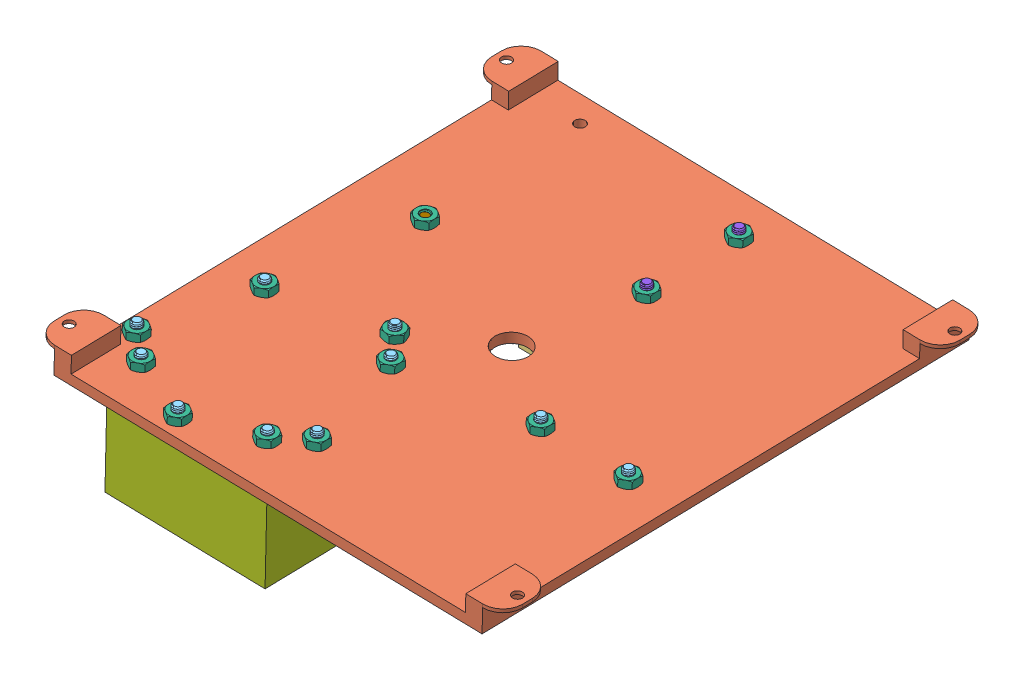
SolidWorks assembly Platform and Parts Assembly, configuration Default. Lengths in mm.
Overall size (140.75 43.07 149.11).
121 component instances, 45 part files, 55 mates.
Components (placement in the parent):
- L298N Motor Driver-1: L298N Motor Driver [Default] at (2.2054 13.8777 390.8162) x (-0.999336 0.034718 0.011037) z (0.010625 -0.012048 0.999871) size (43.5 26 43.5)
- base platform-2: base platform [Default] at (33.5926 16.2793 348.5062) x (-0.999336 0.034718 0.011037) z (0.010625 -0.012048 0.999871) size (139 8 147.5)
- battery holder-1: battery holder [Default] at (70.7076 1.8808 356.6895) x (-0.999336 0.034718 0.011037) z (0.010625 -0.012048 0.999871) size (32 20 15)
- Arduino holder-2: Arduino holder [Default] at (7.3967 9.4765 306.6172) x (0.999336 -0.034718 -0.011037) z (-0.010625 0.012048 -0.999871) size (70.58 5.2 55.34)
- arduino uno-3: arduino uno [Default] at (-25.8848 10.9442 280.3151) x (-0.010625 0.012048 -0.999871) z (-0.999336 0.034718 0.011037) size (53.34 15.26 74.94)
  - arduino uno.STEP-1: arduino uno.STEP [Default] at origin size (53.34 15.26 74.94)
    - USB type b.STEP-1: USB type b.STEP [Default] at (-38.02 0.43 6.35) size (13.91 15.21 16.51)
      - USB SHELL.STEP-1: USB SHELL.STEP [Default] at origin size (13.91 15.21 16.51)
      - USB core.STEP-1: USB core.STEP [Default] at origin size (11.3 10.68 15.75)
      - usb top contact.STEP-1: usb top contact.STEP [Default] at (1.25 6.09 -0.38) size (1 9.67 13.76)
      - usb btm contact.STEP-1: usb btm contact.STEP [Default] at (1.25 4.41 -0.38) size (1 6.84 11.76)
      - usb btm contact.STEP-2: usb btm contact.STEP [Default] at (-1.25 4.41 -0.38) size (1 6.84 11.76)
      - usb top contact.STEP-2: usb top contact.STEP [Default] at (-1.25 6.09 -0.38) size (1 9.67 13.76)
    - dip28.STEP-1: dip28.STEP [Default] at (-16.383 1.5 -46.355) x (0 0 -1) z (1 0 0) size (35.48 7.37 10.1)
      - dip28-0.STEP-1: dip28-0.STEP [Default] at origin size (35.48 2.8 10.1)
      - dip socket pin.STEP-1: dip socket pin.STEP [Default] at (16.51 2.8 -3.81) size (1.7 7.37 1.7)
      - dip socket pin.STEP-2: dip socket pin.STEP [Default] at (16.51 2.8 3.81) size (1.7 7.37 1.7)
      - dip socket pin.STEP-3: dip socket pin.STEP [Default] at (13.97 2.8 -3.81) size (1.7 7.37 1.7)
      - dip socket pin.STEP-4: dip socket pin.STEP [Default] at (13.97 2.8 3.81) size (1.7 7.37 1.7)
      - dip socket pin.STEP-5: dip socket pin.STEP [Default] at (11.43 2.8 -3.81) size (1.7 7.37 1.7)
      - dip socket pin.STEP-6: dip socket pin.STEP [Default] at (11.43 2.8 3.81) size (1.7 7.37 1.7)
      - dip socket pin.STEP-7: dip socket pin.STEP [Default] at (8.89 2.8 -3.81) size (1.7 7.37 1.7)
      - dip socket pin.STEP-8: dip socket pin.STEP [Default] at (8.89 2.8 3.81) size (1.7 7.37 1.7)
      - dip socket pin.STEP-9: dip socket pin.STEP [Default] at (6.35 2.8 -3.81) size (1.7 7.37 1.7)
      - dip socket pin.STEP-10: dip socket pin.STEP [Default] at (6.35 2.8 3.81) size (1.7 7.37 1.7)
      - dip socket pin.STEP-11: dip socket pin.STEP [Default] at (3.81 2.8 -3.81) size (1.7 7.37 1.7)
      - dip socket pin.STEP-12: dip socket pin.STEP [Default] at (3.81 2.8 3.81) size (1.7 7.37 1.7)
      - dip socket pin.STEP-13: dip socket pin.STEP [Default] at (1.27 2.8 -3.81) size (1.7 7.37 1.7)
      - dip socket pin.STEP-14: dip socket pin.STEP [Default] at (1.27 2.8 3.81) size (1.7 7.37 1.7)
      - dip socket pin.STEP-15: dip socket pin.STEP [Default] at (-1.27 2.8 -3.81) size (1.7 7.37 1.7)
      - dip socket pin.STEP-16: dip socket pin.STEP [Default] at (-1.27 2.8 3.81) size (1.7 7.37 1.7)
      - dip socket pin.STEP-17: dip socket pin.STEP [Default] at (-3.81 2.8 -3.81) size (1.7 7.37 1.7)
      - dip socket pin.STEP-18: dip socket pin.STEP [Default] at (-3.81 2.8 3.81) size (1.7 7.37 1.7)
      - dip socket pin.STEP-19: dip socket pin.STEP [Default] at (-6.35 2.8 -3.81) size (1.7 7.37 1.7)
      - dip socket pin.STEP-20: dip socket pin.STEP [Default] at (-6.35 2.8 3.81) size (1.7 7.37 1.7)
      - dip socket pin.STEP-21: dip socket pin.STEP [Default] at (-8.89 2.8 -3.81) size (1.7 7.37 1.7)
      - dip socket pin.STEP-22: dip socket pin.STEP [Default] at (-8.89 2.8 3.81) size (1.7 7.37 1.7)
      - dip socket pin.STEP-23: dip socket pin.STEP [Default] at (-11.43 2.8 -3.81) size (1.7 7.37 1.7)
      - dip socket pin.STEP-24: dip socket pin.STEP [Default] at (-11.43 2.8 3.81) size (1.7 7.37 1.7)
      - dip socket pin.STEP-25: dip socket pin.STEP [Default] at (-13.97 2.8 -3.81) size (1.7 7.37 1.7)
      - dip socket pin.STEP-26: dip socket pin.STEP [Default] at (-13.97 2.8 3.81) size (1.7 7.37 1.7)
      - dip socket pin.STEP-27: dip socket pin.STEP [Default] at (-16.51 2.8 -3.81) size (1.7 7.37 1.7)
      - dip socket pin.STEP-28: dip socket pin.STEP [Default] at (-16.51 2.8 3.81) size (1.7 7.37 1.7)
    - RESET BUTTON.STEP-1: RESET BUTTON.STEP [Default] at (-49.403 0 -6.35) size (6.2 3.1 9.6)
      - RESET CORE.STEP-1: RESET CORE.STEP [Default] at (0 0.1 0) x (-1 0 0) z (0 0 -1) size (6.2 3.1 9.6)
      - RESET.STEP-1: RESET.STEP [Default] at (0 0.1 0) x (0 0 1) z (-1 0 0) size (7.3 2 6.2)
    - unoboard blue.STEP-1: unoboard blue.STEP [Default] at origin size (53.34 1.65 68.58)
    - 47uf CAP Dcase.STEP-1: 47uf CAP Dcase.STEP [Default] at (-9.4141 0 -18.4991) x (0 0 -1) z (1 0 0) size (6.6 5.81 8)
    - power jack.STEP-1: power jack.STEP [Default] at (-7.675 0 1.905) size (11.2 15.2 15.9)
    - 47uf CAP Dcase.STEP-2: 47uf CAP Dcase.STEP [Default] at (-9.4141 0 -25.7132) x (0 0 -1) z (1 0 0) size (6.6 5.81 8)
    - crystal.STEP-1: crystal.STEP [Default] at (-26.162 0 -18.923) x (1 0 0) z (0 0 -1) size (4 5 11)
    - 2pin_header__02.STEP-1: 2pin_header__02.STEP [Default] at (-46.23 0 -15.75) size (5 11.75 2.54)
    - nano - reg.STEP-1: nano - reg.STEP [Default] at (-17.399 0 -7.747) size (6.5 1.69 8.3)
    - led.STEP-1: led.STEP [Default] at (-34.29 0 -27.94) x (0 0 1) z (-1 0 0) size (4 0.85 1.47)
    - 2pin_header__02.STEP-2: 2pin_header__02.STEP [Default] at (-30.43 0 -64.91) x (0 0 1) z (-1 0 0) size (5 11.75 2.54)
    - 2pin_header__02.STEP-3: 2pin_header__02.STEP [Default] at (-27.89 0 -64.91) x (0 0 1) z (-1 0 0) size (5 11.75 2.54)
    - 2pin_header__02.STEP-4: 2pin_header__02.STEP [Default] at (-25.35 0 -64.91) x (0 0 1) z (-1 0 0) size (5 11.75 2.54)
    - 2pin_header__02.STEP-5: 2pin_header__02.STEP [Default] at (-46.23 0 -18.29) size (5 11.75 2.54)
    - 2pin_header__02.STEP-6: 2pin_header__02.STEP [Default] at (-46.23 0 -20.83) size (5 11.75 2.54)
    - atmega16u2.STEP-1: atmega16u2.STEP [Default] at (-34.671 0.06 -20) x (1 0 0) z (0 0 -1) size (5.5 1.01 5.5)
    - led.STEP-2: led.STEP [Default] at (-36.83 0 -27.94) x (0 0 1) z (-1 0 0) size (4 0.85 1.47)
    - led.STEP-3: led.STEP [Default] at (-42.037 0 -27.94) x (0 0 1) z (-1 0 0) size (4 0.85 1.47)
    - led.STEP-4: led.STEP [Default] at (-36.576 0 -58.42) x (0 0 1) z (-1 0 0) size (4 0.85 1.47)
    - 8 PORT HEADER.STEP-1: 8 PORT HEADER.STEP [Default] at (-50.8 0 -45.72) x (0 0 -1) z (1 0 0) size (20.32 10.51 2.41)
    - 8 PORT HEADER.STEP-2: 8 PORT HEADER.STEP [Default] at (-2.54 0 -27.94) x (0 0 -1) z (1 0 0) size (20.32 10.51 2.41)
    - 6 PORT HEADER.STEP-1: 6 PORT HEADER.STEP [Default] at (-2.54 0 -50.8) x (0 0 -1) z (1 0 0) size (15.24 10.51 2.41)
    - 10 PORT HEADER.STEP-1: 10 PORT HEADER.STEP [Default] at (-50.8 0 -18.796) x (0 0 -1) z (1 0 0) size (25.4 10.51 2.41)
    - ATMEL328P.STEP-1: ATMEL328P.STEP [Default] at (-16.383 4.3 -46.355) x (0 0 -1) z (1 0 0) size (35 7.27 7.87)
    - 102 RESISTOR PACK.STEP-1: 102 RESISTOR PACK.STEP [Default] at (-33.782 0 -58.42) size (3.2 0.46 3)
    - 102 RESISTOR PACK.STEP-2: 102 RESISTOR PACK.STEP [Default] at (-39.37 0 -27.94) size (3.2 0.46 3)
    - 103 RESISTOR PACK.STEP-1: 103 RESISTOR PACK.STEP [Default] at (-23.876 0 -27.94) size (3.2 0.46 3)
    - 220 RESISTOR PACK.STEP-1: 220 RESISTOR PACK.STEP [Default] at (-36.83 0 -12.827) size (3.2 0.46 3)
    - 16mhz crystal - measured.STEP-1: 16mhz crystal - measured.STEP [Default] at (-24.892 0 -41.275) x (0 0 -1) z (1 0 0) size (3.4 0.8 2)
    - PADS001.STEP-1: PADS001.STEP [Default] at (-39.878 0.1 -18.288) x (-1 0 0) z (0 0 1) size (4.54 0.1 4.54)
    - 603 cap on pad.STEP-1: 603 cap on pad.STEP [Default] at (-44.45 0 -27.94) x (0 0 -1) z (1 0 0) size (2.76 0.9 1.03)
    - ssot3.STEP-1: ssot3.STEP [Default] at (-26.5 0 -8.128) x (-1 0 0) z (0 0 -1) size (3 1.13 3.09)
    - mf-msmf050-2.STEP-1: mf-msmf050-2.STEP [Default] at (-26.5 0 -4.064) size (5.86 1.02 3.72)
    - 603 cap on pad.STEP-2: 603 cap on pad.STEP [Default] at (-29.845 0 -27.94) x (0 0 -1) z (1 0 0) size (2.76 0.9 1.03)
    - 603 cap on pad.STEP-3: 603 cap on pad.STEP [Default] at (-31.496 0 -27.94) x (0 0 -1) z (1 0 0) size (2.76 0.9 1.03)
    - lmv358.STEP-1: lmv358.STEP [Default] at (-15.24 0 -21.971) x (0 0 -1) z (1 0 0) size (3.7 1.4 2.9)
    - 603 cap on pad.STEP-4: 603 cap on pad.STEP [Default] at (-15.24 0 -18.415) size (2.76 0.9 1.03)
    - 603 cap on pad.STEP-5: 603 cap on pad.STEP [Default] at (-29.845 0 -12.065) x (0 0 1) z (-1 0 0) size (2.76 0.9 1.03)
    - 603 cap on pad.STEP-6: 603 cap on pad.STEP [Default] at (-29.591 0 -22.352) x (0 0 1) z (-1 0 0) size (2.76 0.9 1.03)
    - 603 cap on pad.STEP-7: 603 cap on pad.STEP [Default] at (-29.591 0 -16.002) x (0 0 1) z (-1 0 0) size (2.76 0.9 1.03)
    - 603 cap on pad.STEP-8: 603 cap on pad.STEP [Default] at (-41.91 0 -12.7) x (0 0 1) z (-1 0 0) size (2.76 0.9 1.03)
    - lp2985dgkr.STEP-1: lp2985dgkr.STEP [Default] at (-20.32 0 -19.05) x (0 0 -1) z (1 0 0) size (5.85 1.1 3)
    - cd1206 diode.STEP-1: cd1206 diode.STEP [Default] at (-27.94 0 -59.436) x (0 0 -1) z (1 0 0) size (2.01 0.96 5)
    - cd1206 diode.STEP-2: cd1206 diode.STEP [Default] at (-46.228 0 -13.081) x (0 0 1) z (-1 0 0) size (2.01 0.96 5)
    - 603 resistor.STEP-1: 603 resistor.STEP [Default] at (-29.591 0 -19.05) x (0 0 1) z (-1 0 0) size (2.36 0.61 1.02)
    - blm21.STEP-1: blm21.STEP [Default] at (-45.085 0 -7.62) x (0 0 -1) z (1 0 0) size (2.78 0.95 1.32)
    - m7 diode.STEP-1: m7 diode.STEP [Default] at (-2.794 0 -21.59) x (0 0 -1) z (1 0 0) size (6.66 2.35 2.5)
    - MLC0603.STEP-1: MLC0603.STEP [Default] at (-33.655 0 -12.827) x (0 0 -1) z (1 0 0) size (2.36 0.6 1.02)
    - MLC0603.STEP-2: MLC0603.STEP [Default] at (-39.37 0 -12.827) x (0 0 -1) z (1 0 0) size (2.36 0.6 1.02)
- 18650 Li Ion Battery-2: 18650 Li Ion Battery [Default] at (70.4769 3.1813 331.7044) x (0.999944 0.000054 -0.010625) z (0.010625 -0.012048 0.999871) size (18 18 65.81)
- 3M 8mm 0.5t bolt-2: 3M 8mm 0.5t bolt [92095A181] at (-16.4428 11.1549 409.734) x (0.999393 -0.034851 0.000173) z (-0.034846 -0.999325 -0.011671) size (5.7 5.7 9.83)
- 3M 8mm 0.5t bolt-3: 3M 8mm 0.5t bolt [92095A181] at (-16.8406 11.606 372.2888) x (0.999393 -0.034851 0.000173) z (-0.034846 -0.999325 -0.011671) size (5.7 5.7 9.83)
- 3M 8mm 0.5t bolt-4: 3M 8mm 0.5t bolt [92095A181] at (20.9824 9.8547 409.3206) x (0.999393 -0.034851 0.000173) z (-0.034846 -0.999325 -0.011671) size (5.7 5.7 9.83)
- 3M 8mm 0.5t bolt-5: 3M 8mm 0.5t bolt [92095A181] at (20.5845 10.3059 371.8755) x (0.999393 -0.034851 0.000173) z (-0.034846 -0.999325 -0.011671) size (5.7 5.7 9.83)
- 3M 0.5t nut-1: 3M 0.5t nut [91828A211] at (-16.1866 18.4999 409.8198) x (0.999393 -0.034851 0.000173) z (-0.034846 -0.999325 -0.011671) size (5.5 6.35 2.78)
- 3M 0.5t nut-5: 3M 0.5t nut [91828A211] at (21.2385 17.1997 409.4064) x (0.999393 -0.034851 0.000173) z (-0.034846 -0.999325 -0.011671) size (5.5 6.35 2.78)
- 3M 0.5t nut-6: 3M 0.5t nut [91828A211] at (-16.5845 18.9511 372.3746) x (0.999393 -0.034851 0.000173) z (-0.034846 -0.999325 -0.011671) size (5.5 6.35 2.78)
- 3M 0.5t nut-7: 3M 0.5t nut [91828A211] at (20.8406 17.6509 371.9613) x (0.999393 -0.034851 0.000173) z (-0.034846 -0.999325 -0.011671) size (5.5 6.35 2.78)
- 3M 8mm 0.5t bolt-6: 3M 8mm 0.5t bolt [92095A181] at (84.0348 8.6841 364.1308) x (0.999393 -0.034851 0.000173) z (-0.034846 -0.999325 -0.011671) size (5.7 5.7 9.83)
- 3M 8mm 0.5t bolt-7: 3M 8mm 0.5t bolt [92095A181] at (58.0521 9.5868 364.4178) x (0.999393 -0.034851 0.000173) z (-0.034846 -0.999325 -0.011671) size (5.7 5.7 9.83)
- 3M 0.5t nut-8: 3M 0.5t nut [91828A211] at (84.2735 15.5295 364.2107) x (0.999393 -0.034851 0.000173) z (-0.034846 -0.999325 -0.011671) size (5.5 6.35 2.78)
- 3M 0.5t nut-9: 3M 0.5t nut [91828A211] at (58.2908 16.4322 364.4977) x (0.999393 -0.034851 0.000173) z (-0.034846 -0.999325 -0.011671) size (5.5 6.35 2.78)
- Motor Enclosure-2: Motor Enclosure [Default] at (-21.7812 14.9883 367.3314) x (0.999336 -0.034718 -0.011037) z (-0.034846 -0.999325 -0.011671) size (59.5 59.5 31)
- 3M 8mm 0.5t bolt-8: 3M 8mm 0.5t bolt [92095A181] at (-24.4931 12.0151 402.954) x (0.999393 -0.034851 0.000173) z (-0.034846 -0.999325 -0.011671) size (5.7 5.7 9.83)
- 3M 8mm 0.5t bolt-9: 3M 8mm 0.5t bolt [92095A181] at (2.3972 10.9072 417.5318) x (0.999393 -0.034851 0.000173) z (-0.034846 -0.999325 -0.011671) size (5.7 5.7 9.83)
- 3M 8mm 0.5t bolt-10: 3M 8mm 0.5t bolt [92095A181] at (28.9714 10.1577 402.3635) x (0.999393 -0.034851 0.000173) z (-0.034846 -0.999325 -0.011671) size (5.7 5.7 9.83)
- 3M 8mm 0.5t bolt-11: 3M 8mm 0.5t bolt [92095A181] at (13.8208 11.1351 363.9063) x (0.472551 -0.006186 -0.881282) z (-0.034846 -0.999325 -0.011671) size (5.7 5.7 9.83)
- 3M 0.5t nut-10: 3M 0.5t nut [91828A211] at (-24.2544 18.8605 403.034) x (0.999393 -0.034851 0.000173) z (-0.034846 -0.999325 -0.011671) size (5.5 6.35 2.78)
- 3M 0.5t nut-11: 3M 0.5t nut [91828A211] at (14.0595 17.9805 363.9862) x (-0.783157 0.034559 -0.620863) z (-0.034846 -0.999325 -0.011671) size (5.5 6.35 2.78)
- 3M 0.5t nut-14: 3M 0.5t nut [91828A211] at (29.2101 17.0031 402.4435) x (0.999393 -0.034851 0.000173) z (-0.034846 -0.999325 -0.011671) size (5.5 6.35 2.78)
- 3M 0.5t nut-15: 3M 0.5t nut [91828A211] at (2.6359 17.7526 417.6118) x (0.999393 -0.034851 0.000173) z (-0.034846 -0.999325 -0.011671) size (5.5 6.35 2.78)
- 3M 12mm 0.5t bolt-5: 3M 12mm 0.5t bolt [92095A183] at (40.4317 6.5741 315.1223) x (0.899466 -0.02627 -0.4362) z (-0.034846 -0.999325 -0.011671) size (5.7 5.7 13.83)
- 3M 12mm 0.5t bolt-6: 3M 12mm 0.5t bolt [92095A183] at (40.1348 6.9107 287.1859) x (0.999393 -0.034846 -0.000203) z (-0.034846 -0.999325 -0.011671) size (5.7 5.7 13.83)
- 3M 0.5t nut-16: 3M 0.5t nut [91828A211] at (40.5199 17.9532 287.3149) x (0.999393 -0.034846 -0.000203) z (-0.034846 -0.999325 -0.011671) size (5.5 6.35 2.78)
- 3M 0.5t nut-17: 3M 0.5t nut [91828A211] at (40.8168 17.6166 315.2513) x (0.999393 -0.034846 -0.000203) z (-0.034846 -0.999325 -0.011671) size (5.5 6.35 2.78)
- 3M 0.5t nut-18: 3M 0.5t nut [91828A211] at (-9.7876 19.1967 331.05) x (0.999393 -0.034846 -0.000203) z (-0.034846 -0.999325 -0.011671) size (5.5 6.35 2.78)
- 3M 10mm narrow headed bolt-4: 3M 10mm narrow headed bolt [Default] at (-10.1152 9.803 330.9403) x (0.999393 -0.034846 -0.000203) z (-0.000203 -0.011671 0.999932) size (3.5 12 3.5)
Mates (geometry in assembly coordinates):
- Coincident4: coincident anti-aligned: plane of L298N Motor Driver-1 through (2.2054 13.8777 390.8162) normal (0.034846 0.999325 0.011671); plane of base platform-2 through (33.488 13.2814 348.4712) normal (-0.034846 -0.999325 -0.011671)
- Coincident5: coincident anti-aligned: line of L298N Motor Driver-1 through (24.172 12.8605 412.3234) axis (-0.999336 0.034718 0.011037); line of base platform-2 through (-19.2991 14.3707 412.8035) axis (0.999336 -0.034718 -0.011037)
- Coincident6: coincident aligned: line of L298N Motor Driver-1 through (-19.2991 14.3707 412.8035) axis (-0.010625 0.012048 -0.999871); line of base platform-2 through (-19.2991 14.3707 412.8035) axis (-0.010625 0.012048 -0.999871)
- Coincident35: coincident anti-aligned: plane of base platform-2 through (33.488 13.2814 348.4712) normal (-0.034846 -0.999325 -0.011671); plane of battery holder-1 through (81.2088 11.3461 371.6939) normal (0.034846 0.999325 0.011671)
- Coincident36: coincident anti-aligned: circle of base platform-2; circle of battery holder-1
- Coincident37: coincident anti-aligned: circle of base platform-2; circle of battery holder-1
- Coincident41: coincident anti-aligned: plane of base platform-2 through (33.488 13.2814 348.4712) normal (-0.034846 -0.999325 -0.011671); plane of Arduino holder-2 through (7.5779 14.6729 306.6779) normal (0.034846 0.999325 0.011671)
- Coincident42: coincident aligned: circle of base platform-2; circle of Arduino holder-2
- Coincident43: coincident anti-aligned: plane of Arduino holder-2 through (7.8264 13.3523 333.3328) normal (-0.010625 0.012048 -0.999871); plane of arduino uno-3/arduino uno.STEP-1/unoboard blue.STEP-1 through (-25.2606 11.9504 333.6675) normal (0.010625 -0.012048 0.999871)
- Coincident44: coincident anti-aligned: plane of Arduino holder-2 through (43.0794 12.439 306.2737) normal (-0.999336 0.034718 0.011037); plane of arduino uno-3/arduino uno.STEP-1/unoboard blue.STEP-1 through (42.7612 10.1509 284.6567) normal (0.999336 -0.034718 -0.011037)
- Coincident45: coincident aligned: line of Arduino holder-2 through (-25.3181 10.3015 333.6482) axis (-0.010625 0.012048 -0.999871); line of arduino uno-3/arduino uno.STEP-1/unoboard blue.STEP-1 through (-25.3181 10.3015 333.6482) axis (-0.010625 0.012048 -0.999871)
- Coincident47: coincident anti-aligned: circle of battery holder-1; circle of 18650 Li Ion Battery-2
- Coincident48: coincident anti-aligned: circle of battery holder-1; circle of 18650 Li Ion Battery-2
- Coincident51: coincident anti-aligned: plane of L298N Motor Driver-1 through (2.1531 12.3787 390.7987) normal (-0.034846 -0.999325 -0.011671); plane of 3M 8mm 0.5t bolt-2 through (-16.3836 12.837 406.9034) normal (0.034846 0.999325 0.011671)
- Concentric8: concentric anti-aligned: circle of L298N Motor Driver-1; circle of 3M 8mm 0.5t bolt-2
- Coincident53: coincident anti-aligned: plane of base platform-2 through (33.5926 16.2793 348.5062) normal (0.034846 0.999325 0.011671); plane of 3M 0.5t nut-1 through (-18.9777 17.378 411.3929) normal (-0.034846 -0.999325 -0.011671)
- Concentric9: concentric anti-aligned: circle of base platform-2; circle of 3M 0.5t nut-1
- Coincident56: coincident anti-aligned: plane of battery holder-1 through (87.0106 10.3192 356.6179) normal (-0.034846 -0.999325 -0.011671); plane of 3M 8mm 0.5t bolt-6 through (84.094 10.3662 361.3002) normal (0.034846 0.999325 0.011671)
- Concentric11: concentric anti-aligned: circle of battery holder-1; circle of 3M 6mm 0.5t bolt-2
- Coincident58: coincident anti-aligned: plane of base platform-2 through (33.5926 16.2793 348.5062) normal (0.034846 0.999325 0.011671); plane of 3M 0.5t nut-8 through (81.4825 14.4076 365.7839) normal (-0.034846 -0.999325 -0.011671)
- Concentric12: concentric aligned: circle of 3M 6mm 0.5t bolt-2; circle of 3M 0.5t nut-8
- Coincident60: coincident anti-aligned: plane of base platform-2 through (33.488 13.2814 348.4712) normal (-0.034846 -0.999325 -0.011671); plane of Motor Enclosure-2 through (-21.7812 14.9883 367.3314) normal (0.034846 0.999325 0.011671)
- Concentric13: concentric aligned: circle of base platform-2; circle of Motor Enclosure-2
- Concentric14: concentric aligned: circle of base platform-2; circle of Motor Enclosure-2
- Concentric15: concentric aligned: circle of base platform-2; circle of Motor Enclosure-2
- Coincident65: coincident anti-aligned: plane of Motor Enclosure-2 through (-27.3539 13.6778 410.5054) normal (-0.034846 -0.999325 -0.011671); plane of 3M 8mm 0.5t bolt-8 through (-24.4339 13.6972 400.1235) normal (0.034846 0.999325 0.011671)
- Concentric16: concentric anti-aligned: circle of Motor Enclosure-2; circle of 3M 8mm 0.5t bolt-8
- Coincident67: coincident anti-aligned: plane of Motor Enclosure-2 through (9.9816 12.2595 420.4679) normal (-0.034846 -0.999325 -0.011671); plane of 3M 8mm 0.5t bolt-9 through (2.4564 12.5893 414.7013) normal (0.034846 0.999325 0.011671)
- Concentric17: concentric anti-aligned: circle of Motor Enclosure-2; circle of 3M 8mm 0.5t bolt-9
- Coincident69: coincident anti-aligned: plane of Motor Enclosure-2 through (31.9472 11.7928 394.8506) normal (-0.034846 -0.999325 -0.011671); plane of 3M 8mm 0.5t bolt-10 through (29.0306 11.8398 399.533) normal (0.034846 0.999325 0.011671)
- Concentric18: concentric anti-aligned: circle of Motor Enclosure-2; circle of 3M 8mm 0.5t bolt-10
- Concentric19: concentric anti-aligned: circle of Motor Enclosure-2; circle of 3M 8mm 0.5t bolt-11
- Coincident72: coincident anti-aligned: plane of Motor Enclosure-2 through (6.3514 13.0805 361.0087) normal (-0.034846 -0.999325 -0.011671); plane of 3M 8mm 0.5t bolt-11 through (11.3686 12.8872 362.5791) normal (0.034846 0.999325 0.011671)
- Concentric20: concentric anti-aligned: circle of 3M 8mm 0.5t bolt-8; circle of 3M 0.5t nut-10
- Coincident73: coincident anti-aligned: plane of base platform-2 through (33.5926 16.2793 348.5062) normal (0.034846 0.999325 0.011671); plane of 3M 0.5t nut-10 through (-27.0454 17.7386 404.6071) normal (-0.034846 -0.999325 -0.011671)
- Concentric21: concentric anti-aligned: circle of 3M 8mm 0.5t bolt-11; circle of 3M 0.5t nut-11
- Coincident74: coincident anti-aligned: plane of base platform-2 through (33.5926 16.2793 348.5062) normal (0.034846 0.999325 0.011671); plane of 3M 0.5t nut-11 through (17.1571 16.6664 364.4351) normal (-0.034846 -0.999325 -0.011671)
- Coincident76: coincident anti-aligned: plane of base platform-2 through (33.5926 16.2793 348.5062) normal (0.034846 0.999325 0.011671); plane of 3M 0.5t nut-14 through (26.4191 15.8812 404.0166) normal (-0.034846 -0.999325 -0.011671)
- Concentric24: concentric anti-aligned: circle of 3M 8mm 0.5t bolt-10; circle of 3M 0.5t nut-14
- Coincident77: coincident anti-aligned: plane of base platform-2 through (33.5926 16.2793 348.5062) normal (0.034846 0.999325 0.011671); plane of 3M 0.5t nut-15 through (-0.1551 16.6307 419.1849) normal (-0.034846 -0.999325 -0.011671)
- Concentric25: concentric aligned: circle of 3M 8mm 0.5t bolt-9; circle of 3M 0.5t nut-15
- Concentric29: concentric anti-aligned: circle of base platform-2; circle of Arduino holder-2
- Concentric30: concentric anti-aligned: circle of base platform-2; circle of Arduino holder-2
- Coincident86: coincident anti-aligned: plane of arduino uno-3/arduino uno.STEP-1/unoboard blue.STEP-1 through (-25.8848 10.9442 280.3151) normal (-0.034846 -0.999325 -0.011671); plane of 3M 12mm 0.5t bolt-5 through (39.2477 8.2962 312.5772) normal (0.034846 0.999325 0.011671)
- Concentric35: concentric anti-aligned: circle of Arduino holder-2; circle of 3M 12mm 0.5t bolt-5
- Coincident89: coincident anti-aligned: plane of arduino uno-3/arduino uno.STEP-1/unoboard blue.STEP-1 through (-25.8848 10.9442 280.3151) normal (-0.034846 -0.999325 -0.011671); plane of 3M 12mm 0.5t bolt-6 through (40.1929 8.5928 284.3554) normal (0.034846 0.999325 0.011671)
- Concentric36: concentric anti-aligned: circle of Arduino holder-2; circle of 3M 12mm 0.5t bolt-6
- Coincident90: coincident anti-aligned: plane of base platform-2 through (33.5926 16.2793 348.5062) normal (0.034846 0.999325 0.011671); plane of 3M 0.5t nut-16 through (37.7294 16.8313 288.889) normal (-0.034846 -0.999325 -0.011671)
- Concentric37: concentric aligned: circle of 3M 12mm 0.5t bolt-6; circle of 3M 0.5t nut-16
- Coincident91: coincident anti-aligned: plane of base platform-2 through (33.5926 16.2793 348.5062) normal (0.034846 0.999325 0.011671); plane of 3M 0.5t nut-17 through (38.0263 16.4947 316.8254) normal (-0.034846 -0.999325 -0.011671)
- Concentric38: concentric anti-aligned: circle of Arduino holder-2; circle of 3M 0.5t nut-17
- Coincident92: coincident anti-aligned: plane of base platform-2 through (33.5926 16.2793 348.5062) normal (0.034846 0.999325 0.011671); plane of 3M 0.5t nut-18 through (-12.5781 18.0748 332.6242) normal (-0.034846 -0.999325 -0.011671)
- Coincident93: coincident anti-aligned: plane of arduino uno-3/arduino uno.STEP-1/unoboard blue.STEP-1 through (-25.8848 10.9442 280.3151) normal (-0.034846 -0.999325 -0.011671); plane of 3M 10mm narrow headed bolt-4 through (-10.1152 9.803 330.9403) normal (0.034846 0.999325 0.011671)
- Concentric40: concentric anti-aligned: circle of Arduino holder-2; circle of 3M 10mm narrow headed bolt-4
- Concentric41: concentric aligned: circle of 3M 0.5t nut-18; circle of 3M 10mm narrow headed bolt-4
